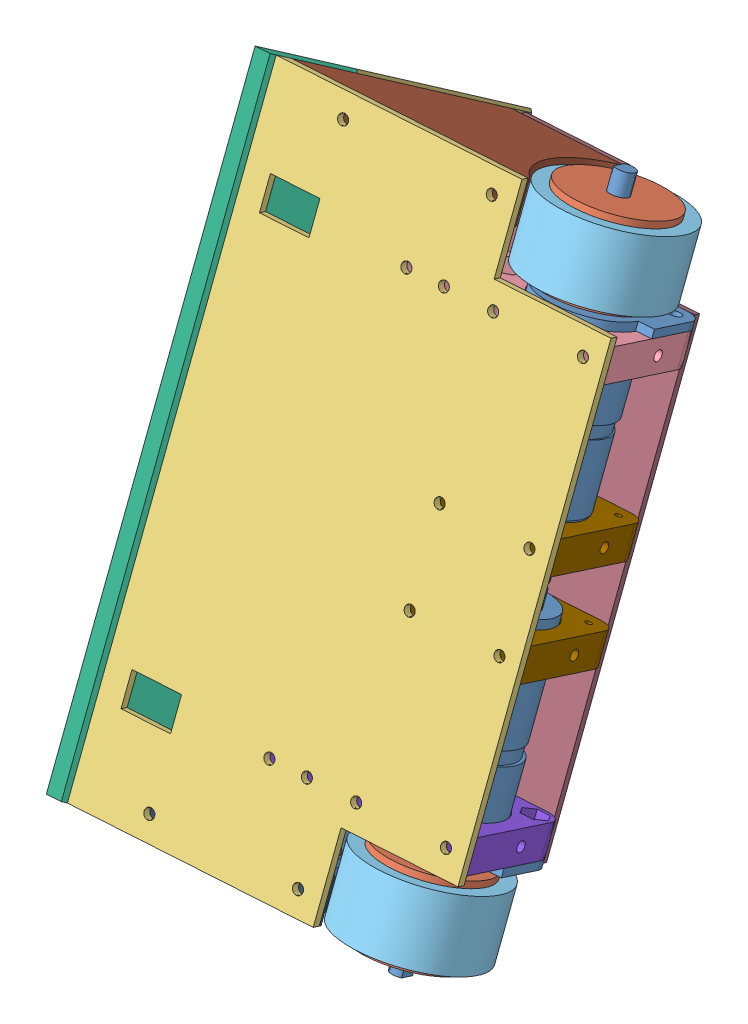
SolidWorks assembly RyO_XL, configuration Predeterminado. Lengths in mm.
Overall size (125.62 209.31 123.71).
23 component instances, 18 part files, 58 mates.
Components (placement in the parent):
- SP6_7W_EJEd6L10B-3: SP6_7W_EJEd6L10B [Predeterminado] at (18.001 16.4515 185.6838) x (-0.101969 -0.366807 -0.924692) z (0.994757 -0.030282 -0.097683) size (35 104.5 40)
- Llanta_D50L19-1: Llanta_D50L19 [Predeterminado] at (18.4238 -33.7579 205.5543) x (-0.993599 0.034235 0.107648) z (-0.112689 -0.36646 -0.923585) size (33 25 33)
- Base_chasis_RyO_XL-1: Base_chasis_RyO_XL [Predeterminado] at (-21.3225 65.5802 189.7273) x (0.00783 -0.929804 0.367972) z (0.994757 -0.030282 -0.097683) size (195 2.5 111.7)
- Soporte_motores_APYS_IZQ_XL-2: Soporte_motores_APYS_IZQ_XL [Predeterminado] at (17.2738 103.388 151.2779) x (0.994757 -0.030282 -0.097683) z (0.101969 0.366807 0.924692) size (66.72 10 35.25)
- SP6_7W_EJEd6L10B-2: SP6_7W_EJEd6L10B [Predeterminado] at (17.309 99.2039 152.9338) x (-0.101969 -0.366807 -0.924692) z (-0.994757 0.030282 0.097683) size (35 104.5 40)
- Llanta_D50L19-2: Llanta_D50L19 [Predeterminado] at (16.8862 149.4133 133.0633) x (0.676672 -0.266007 -0.686553) z (-0.736243 -0.254372 -0.627089) size (33 25 33)
- Cubierta_D42L15-1: Cubierta_D42L15 [Predeterminado] at (18.2437 -12.3724 197.0909) x (0.836326 0.207815 0.507318) z (0.548177 -0.303772 -0.779246) size (42 21 42)
- Cubierta_D42L15-2: Cubierta_D42L15 [Predeterminado] at (17.0663 128.0278 141.5267) x (0.999968 0.00783 -0.001493) z (-0.001493 0.367972 0.929836) size (42 21 42)
- Cuchilla_Garlopa-1: Cuchilla_Garlopa [Predeterminado] at (-67.5893 155.8983 153.9648) x (-0.688932 0.261701 0.675933) z (0.724784 0.2588 0.638522) size (25 195 3)
- pololu-38-khz-ir-proximity-sensor-1: pololu-38-khz-ir-proximity-sensor [Predeterminado] at (-51.0023 115.765 164.982) x (0.00783 -0.929804 0.367972) z (-0.101969 -0.366807 -0.924692) size (10.16 15.24 5.37)
- pololu-38-khz-ir-proximity-sensor-2: pololu-38-khz-ir-proximity-sensor [Predeterminado] at (-50.2049 21.0737 202.4563) x (0.00783 -0.929804 0.367972) z (-0.101969 -0.366807 -0.924692) size (10.16 15.24 5.37)
- Soporte_motores_APYS_DER_XL-1: Soporte_motores_APYS_DER_XL [Predeterminado] at (18.3494 -24.9248 202.0585) x (0.994757 -0.030282 -0.097683) z (0.101969 0.366807 0.924692) size (66.72 10 35.25)
- g2-high-power-motor-driver-md31a.step-1: g2-high-power-motor-driver-md31a.step [Predeterminado] at (15.7291 -43.1589 53.3885) x (-0.008523 0 0.999964) z (-0.999964 0 -0.008523) size (33.02 20.32 9.57) (hidden)
- Soporte_motores_INTERNO_APYS_XL-1: Soporte_motores_INTERNO_APYS_XL [Predeterminado] at (17.9587 21.4701 183.6977) x (0.994757 -0.030282 -0.097683) z (0.101969 0.366807 0.924692) size (39.99 10 35.25)
- Soporte_motores_INTERNO_APYS_XL-3: Soporte_motores_INTERNO_APYS_XL [Predeterminado] at (17.7395 47.5046 173.3944) x (0.994757 -0.030282 -0.097683) z (0.101969 0.366807 0.924692) size (39.99 10 35.25)
- 2022-RyO-XL-Lateral_DER-1: 2022-RyO-XL-Lateral_DER [Predeterminado] at (3.9551 -14.8948 216.1591) x (-0.994757 0.030282 0.097683) z (0.101969 0.366807 0.924692) size (76.35 12.75 35.25)
- 2022-RyO-XL-Lateral_IZQ-2: 2022-RyO-XL-Lateral_IZQ [Predeterminado] at (2.6279 142.707 153.7879) x (-0.994757 0.030282 0.097683) z (0.101969 0.366807 0.924692) size (76.35 12.75 35.25)
- Lipo_Tattu_1500_4S-1: Lipo_Tattu_1500_4S [Predeterminado] at (9.925 4.3149 149.7532) x (-0.994757 0.030282 0.097683) z (-0.101969 -0.366807 -0.924692) size (37 85 33) (hidden)
- Soporte Sensores-1: Soporte Sensores [Predeterminado] at (-31.7932 51.9347 155.4704) x (0.00783 -0.929804 0.367972) z (-0.724784 -0.2588 -0.638522) size (195 43 18.19)
- Tapa_Posterior-1: Tapa_Posterior [Predeterminado] at (-29.0129 51.1103 153.328) x (0.00783 -0.929804 0.367972) z (0.101969 0.366807 0.924692) size (195 62 2)
- CoverBateria-1: CoverBateria [Predeterminado] at (-7.1283 50.4441 151.1789) x (0.994757 -0.030282 -0.097683) z (-0.101969 -0.366807 -0.924692) size (60.29 144 41) (hidden)
- HC-SR04-1: HC-SR04 [Predeterminado] at (-20.1223 30.7171 162.7682) x (-0.00783 0.929804 -0.367972) z (0.994757 -0.030282 -0.097683) size (45 20.3 18.25)
- Plomo_Central-1: Plomo_Central [Predeterminado] at (-62.9124 13.8658 212.1241) x (0.994757 -0.030282 -0.097683) z (0.101969 0.366807 0.924692) size (60 112 23)
Mates (geometry in assembly coordinates):
- Concéntrica2: concentric anti-aligned: cylinder of SP6_7W_EJEd6L10B-3 through (18.4747 -39.8016 207.9461) axis (-0.00783 0.929804 -0.367972) radius 3; cylinder of Llanta_D50L19-1 through (18.2281 -10.5128 196.355) axis (0.00783 -0.929804 0.367972) radius 3
- Concéntrica5: concentric aligned: cylinder of Soporte_motores_APYS_IZQ_XL-2 through (17.1172 121.9841 143.9185) axis (0.00783 -0.929804 0.367972) radius 15.25; cylinder of SP6_7W_EJEd6L10B-2 through (17.1172 121.9841 143.9185) axis (0.00783 -0.929804 0.367972) radius 15
- Coincidente5: coincident anti-aligned: plane of SP6_7W_EJEd6L10B-2 through (33.5681 127.032 156.3236) normal (0.00783 -0.929804 0.367972); plane of Soporte_motores_APYS_IZQ_XL-2 through (46.4648 126.7319 155.2909) normal (-0.00783 0.929804 -0.367972)
- Concéntrica6: concentric aligned: cylinder of Soporte_motores_APYS_IZQ_XL-2 through (0.6663 116.9362 131.5133) axis (0.00783 -0.929804 0.367972) radius 1; cylinder of SP6_7W_EJEd6L10B-2 through (0.6467 119.2607 130.5934) axis (0.00783 -0.929804 0.367972) radius 2
- Coincidente6: coincident anti-aligned: plane of Base_chasis_RyO_XL-1 through (-21.5774 64.6631 187.4156) normal (-0.101969 -0.366807 -0.924692); plane of Soporte_motores_APYS_DER_XL-1 through (19.9044 -19.331 216.1601) normal (0.101969 0.366807 0.924692)
- Concéntrica8: concentric anti-aligned: cylinder of SP6_7W_EJEd6L10B-2 through (16.8353 155.457 130.6715) axis (0.00783 -0.929804 0.367972) radius 3; cylinder of Llanta_D50L19-2 through (17.082 126.1682 142.2626) axis (-0.00783 0.929804 -0.367972) radius 3
- Concéntrica10: concentric anti-aligned: cylinder of Llanta_D50L19-1 through (18.2281 -10.5128 196.355) axis (0.00783 -0.929804 0.367972) radius 15; cylinder of Cubierta_D42L15-1 through (18.4082 -31.8983 204.8183) axis (-0.00783 0.929804 -0.367972) radius 12.5
- Coincidente9: coincident anti-aligned: plane of Cubierta_D42L15-1 through (18.4082 -31.8983 204.8183) normal (0.00783 -0.929804 0.367972); plane of Llanta_D50L19-1 through (18.4082 -31.8983 204.8183) normal (-0.00783 0.929804 -0.367972)
- Concéntrica11: concentric anti-aligned: cylinder of Llanta_D50L19-2 through (17.082 126.1682 142.2626) axis (-0.00783 0.929804 -0.367972) radius 15; cylinder of Cubierta_D42L15-2 through (16.9019 147.5537 133.7992) axis (0.00783 -0.929804 0.367972) radius 12.5
- Coincidente10: coincident anti-aligned: plane of Llanta_D50L19-2 through (16.9019 147.5537 133.7992) normal (0.00783 -0.929804 0.367972); plane of Cubierta_D42L15-2 through (16.9019 147.5537 133.7992) normal (-0.00783 0.929804 -0.367972)
- Coincidente11: coincident anti-aligned: plane of Base_chasis_RyO_XL-1 through (-70.2264 198.6717 139.6216) normal (-0.724784 -0.2588 -0.638522); plane of Cuchilla_Garlopa-1 through (-57.2092 -28.7765 217.0331) normal (0.724784 0.2588 0.638522)
- Coincidente13: coincident aligned: plane of Base_chasis_RyO_XL-1 through (-20.814 -25.9927 223.2928) normal (0.00783 -0.929804 0.367972); plane of Cuchilla_Garlopa-1 through (-66.0625 -25.4135 225.7193) normal (0.00783 -0.929804 0.367972)
- Distancia8: distance = 5 mm anti-aligned: plane of pololu-38-khz-ir-proximity-sensor-2 through (-50.2049 21.0737 202.4563) normal (0.101969 0.366807 0.924692); plane of Base_chasis_RyO_XL-1 through (-21.5774 64.6631 187.4156) normal (-0.101969 -0.366807 -0.924692)
- Concéntrica18: concentric anti-aligned: cylinder of Soporte_motores_APYS_DER_XL-1 through (-12.7337 -8.138 177.1973) axis (0.101969 0.366807 0.924692) radius 1.625; cylinder of Base_chasis_RyO_XL-1 through (-8.1196 8.4604 219.0405) axis (-0.101969 -0.366807 -0.924692) radius 1.625
- Coincidente27: coincident anti-aligned: plane of Base_chasis_RyO_XL-1 through (-21.5774 64.6631 187.4156) normal (-0.101969 -0.366807 -0.924692); plane of Soporte_motores_APYS_IZQ_XL-2 through (18.8288 108.9818 165.3795) normal (0.101969 0.366807 0.924692)
- Paralelo4: parallel aligned: plane of Base_chasis_RyO_XL-1 through (-20.814 -25.9927 223.2928) normal (0.00783 -0.929804 0.367972); plane of Soporte_motores_APYS_DER_XL-1 through (50.2272 -2.5875 203.4709) normal (0.00783 -0.929804 0.367972)
- Concéntrica21: concentric anti-aligned: cylinder of SP6_7W_EJEd6L10B-3 through (18.1928 -6.3287 194.6991) axis (-0.00783 0.929804 -0.367972) radius 15; cylinder of Soporte_motores_APYS_DER_XL-1 through (18.1928 -6.3287 194.6991) axis (0.00783 -0.929804 0.367972) radius 15.25
- Concéntrica22: concentric aligned: circle of SP6_7W_EJEd6L10B-3; cylinder of Soporte_motores_APYS_DER_XL-1 through (1.742 -11.3766 182.294) axis (0.00783 -0.929804 0.367972) radius 1
- Concéntrica23: concentric anti-aligned: cylinder of SP6_7W_EJEd6L10B-3 through (31.6042 -14.6095 180.2834) axis (-0.00783 0.929804 -0.367972) radius 2; cylinder of Soporte_motores_APYS_DER_XL-1 through (31.5847 -12.285 179.3635) axis (0.00783 -0.929804 0.367972) radius 1
- Coincidente29: coincident anti-aligned: plane of SP6_7W_EJEd6L10B-3 through (4.801 -0.3724 210.0347) normal (-0.00783 0.929804 -0.367972); plane of Soporte_motores_APYS_DER_XL-1 through (50.2272 -2.5875 203.4709) normal (0.00783 -0.929804 0.367972)
- Distancia9: distance = 3 mm anti-aligned: plane of pololu-38-khz-ir-proximity-sensor-2 through (-50.229 11.2543 205.2554) normal (0.00783 -0.929804 0.367972); plane of Soporte_motores_APYS_DER_XL-1 through (39.3098 7.0405 200.8555) normal (-0.00783 0.929804 -0.367972)
- Concéntrica27: concentric anti-aligned: cylinder of Base_chasis_RyO_XL-1 through (-20.6012 127.8247 173.0673) axis (-0.101969 -0.366807 -0.924692) radius 1.625; cylinder of Soporte_motores_APYS_IZQ_XL-2 through (-25.2154 111.2263 131.2241) axis (0.101969 0.366807 0.924692) radius 1.625
- Concéntrica32: concentric anti-aligned: cylinder of Base_chasis_RyO_XL-1 through (6.5848 54.491 199.1595) axis (-0.101969 -0.366807 -0.924692) radius 1.625; cylinder of Soporte_motores_INTERNO_APYS_XL-1 through (4.3415 46.4213 178.8163) axis (0.101969 0.366807 0.924692) radius 1.625
- Concéntrica33: concentric anti-aligned: cylinder of Base_chasis_RyO_XL-1 through (34.0889 53.6538 196.4587) axis (-0.101969 -0.366807 -0.924692) radius 1.625; cylinder of Soporte_motores_INTERNO_APYS_XL-1 through (31.8457 45.584 176.1155) axis (0.101969 0.366807 0.924692) radius 1.625
- Coincidente40: coincident anti-aligned: plane of Base_chasis_RyO_XL-1 through (-21.5774 64.6631 187.4156) normal (-0.101969 -0.366807 -0.924692); plane of Soporte_motores_INTERNO_APYS_XL-1 through (19.5137 27.0639 197.7992) normal (0.101969 0.366807 0.924692)
- Concéntrica34: concentric anti-aligned: cylinder of Base_chasis_RyO_XL-1 through (6.3656 80.5256 188.8563) axis (-0.101969 -0.366807 -0.924692) radius 1.625; cylinder of Soporte_motores_INTERNO_APYS_XL-3 through (4.1223 72.4558 168.5131) axis (0.101969 0.366807 0.924692) radius 1.625
- Concéntrica35: concentric anti-aligned: cylinder of Base_chasis_RyO_XL-1 through (33.8697 79.6883 186.1555) axis (-0.101969 -0.366807 -0.924692) radius 1.625; cylinder of Soporte_motores_INTERNO_APYS_XL-3 through (31.6264 71.6185 165.8122) axis (0.101969 0.366807 0.924692) radius 1.625
- Coincidente41: coincident anti-aligned: plane of Base_chasis_RyO_XL-1 through (-21.5774 64.6631 187.4156) normal (-0.101969 -0.366807 -0.924692); plane of Soporte_motores_INTERNO_APYS_XL-3 through (19.2945 53.0984 187.496) normal (0.101969 0.366807 0.924692)
- Distancia12: distance = 3 mm anti-aligned: plane of pololu-38-khz-ir-proximity-sensor-1 through (-66.266 115.8538 165.5312) normal (-0.00783 0.929804 -0.367972); plane of Soporte_motores_APYS_IZQ_XL-2 through (38.3907 116.7572 157.4344) normal (0.00783 -0.929804 0.367972)
- Coincidente43: coincident aligned: plane of pololu-38-khz-ir-proximity-sensor-1 through (-51.0023 115.765 164.982) normal (0.101969 0.366807 0.924692); plane of pololu-38-khz-ir-proximity-sensor-2 through (-50.2049 21.0737 202.4563) normal (0.101969 0.366807 0.924692)
- Coincidente44: coincident aligned: plane of pololu-38-khz-ir-proximity-sensor-1 through (-51.1059 115.3923 164.0425) normal (0.994757 -0.030282 -0.097683); plane of pololu-38-khz-ir-proximity-sensor-2 through (-50.3085 20.7011 201.5168) normal (0.994757 -0.030282 -0.097683)
- Concéntrica36: concentric aligned: cylinder of 2022-RyO-XL-Lateral_DER-1 through (-5.9837 -30.8945 191.5681) axis (0.101969 0.366807 0.924692) radius 1.625; cylinder of Base_chasis_RyO_XL-1 through (-2.9632 -20.0292 218.9587) axis (0.101969 0.366807 0.924692) radius 1.625
- Coincidente45: coincident anti-aligned: plane of Base_chasis_RyO_XL-1 through (-21.5774 64.6631 187.4156) normal (-0.101969 -0.366807 -0.924692); plane of 2022-RyO-XL-Lateral_DER-1 through (4.0549 -26.7498 220.8508) normal (0.101969 0.366807 0.924692)
- Concéntrica40: concentric anti-aligned: cylinder of Base_chasis_RyO_XL-1 through (-47.4867 -14.9747 232.6779) axis (-0.101969 -0.366807 -0.924692) radius 1.625; cylinder of 2022-RyO-XL-Lateral_DER-1 through (-51.5268 -29.5082 196.0403) axis (0.101969 0.366807 0.924692) radius 1.625
- Coincidente47: coincident anti-aligned: plane of Base_chasis_RyO_XL-1 through (-21.5774 64.6631 187.4156) normal (-0.101969 -0.366807 -0.924692); plane of 2022-RyO-XL-Lateral_IZQ-2 through (2.7278 130.852 158.4795) normal (0.101969 0.366807 0.924692)
- Concéntrica41: concentric aligned: cylinder of Base_chasis_RyO_XL-1 through (-4.3804 148.2653 152.3558) axis (0.101969 0.366807 0.924692) radius 1.625; cylinder of 2022-RyO-XL-Lateral_IZQ-2 through (-7.4008 137.4 124.9651) axis (0.101969 0.366807 0.924692) radius 1.625
- Concéntrica42: concentric anti-aligned: cylinder of Base_chasis_RyO_XL-1 through (-48.9038 153.3198 166.075) axis (-0.101969 -0.366807 -0.924692) radius 1.625; cylinder of 2022-RyO-XL-Lateral_IZQ-2 through (-52.944 138.7863 129.4374) axis (0.101969 0.366807 0.924692) radius 1.625
- Distancia14: distance = 55 mm aligned: plane of Lipo_Tattu_1500_4S-1 through (9.925 4.3149 149.7532) normal (0.00783 -0.929804 0.367972); plane of Base_chasis_RyO_XL-1 through (-20.814 -25.9927 223.2928) normal (0.00783 -0.929804 0.367972)
- Distancia16: distance = 2 mm anti-aligned: plane of Llanta_D50L19-2 through (17.082 126.1682 142.2626) normal (0.00783 -0.929804 0.367972); plane of SP6_7W_EJEd6L10B-2 through (33.5485 129.3565 155.4037) normal (-0.00783 0.929804 -0.367972)
- Distancia17: distance = 2 mm anti-aligned: plane of Llanta_D50L19-1 through (18.2281 -10.5128 196.355) normal (-0.00783 0.929804 -0.367972); plane of SP6_7W_EJEd6L10B-3 through (4.8206 -2.6969 210.9546) normal (0.00783 -0.929804 0.367972)
- Concéntrica43: concentric anti-aligned: cylinder of 2022-RyO-XL-Lateral_IZQ-2 through (-35.5929 143.1766 138.4632) axis (-0.724784 -0.2588 -0.638522) radius 1.625; cylinder of Soporte Sensores-1 through (-45.015 139.8122 130.1624) axis (0.724784 0.2588 0.638522) radius 1.625
- Concéntrica47: concentric anti-aligned: cylinder of 2022-RyO-XL-Lateral_DER-1 through (-34.1659 -26.2801 205.5261) axis (-0.724784 -0.2588 -0.638522) radius 1.625; cylinder of Soporte Sensores-1 through (-43.5881 -29.6445 197.2253) axis (0.724784 0.2588 0.638522) radius 1.625
- Coincidente48: coincident anti-aligned: plane of 2022-RyO-XL-Lateral_IZQ-2 through (-69.6738 133.056 165.5892) normal (-0.724784 -0.2588 -0.638522); plane of Soporte Sensores-1 through (-31.7932 51.9347 155.4704) normal (0.724784 0.2588 0.638522)
- Coincidente49: coincident anti-aligned: plane of Cuchilla_Garlopa-1 through (-59.3836 -29.5529 215.1176) normal (0.688932 -0.261701 -0.675933); plane of Soporte Sensores-1 through (-59.3836 -29.5529 215.1176) normal (-0.688932 0.261701 0.675933)
- Concéntrica48: concentric aligned: cylinder of 2022-RyO-XL-Lateral_IZQ-2 through (-18.9647 149.2906 153.5584) axis (-0.101969 -0.366807 -0.924692) radius 1.625; cylinder of Tapa_Posterior-1 through (-22.5591 136.3603 120.9621) axis (-0.101969 -0.366807 -0.924692) radius 1.625
- Concéntrica49: concentric aligned: cylinder of 2022-RyO-XL-Lateral_DER-1 through (-17.5377 -20.1661 220.6213) axis (-0.101969 -0.366807 -0.924692) radius 1.625; cylinder of Tapa_Posterior-1 through (-21.1322 -33.0965 188.025) axis (-0.101969 -0.366807 -0.924692) radius 1.625
- Coincidente50: coincident anti-aligned: plane of 2022-RyO-XL-Lateral_IZQ-2 through (-32.3805 121.67 127.8725) normal (-0.101969 -0.366807 -0.924692); plane of Tapa_Posterior-1 through (-28.809 51.8439 155.1773) normal (0.101969 0.366807 0.924692)
- Coincidente51: coincident anti-aligned: plane of Lipo_Tattu_1500_4S-1 through (29.345 88.8403 131.9259) normal (0.101969 0.366807 0.924692); plane of Tapa_Posterior-1 through (-29.0129 51.1103 153.328) normal (-0.101969 -0.366807 -0.924692)
- Distancia18: distance = 3 mm aligned: plane of Lipo_Tattu_1500_4S-1 through (25.98 76.7357 101.411) normal (0.994757 -0.030282 -0.097683); plane of Tapa_Posterior-1 through (33.4258 -16.5145 175.431) normal (0.994757 -0.030282 -0.097683)
- Concéntrica50: concentric anti-aligned: cylinder of Tapa_Posterior-1 through (18.4383 109.8978 126.9384) axis (-0.101969 -0.366807 -0.924692) radius 1.625; cylinder of CoverBateria-1 through (17.9284 108.0638 122.3149) axis (0.101969 0.366807 0.924692) radius 1.625
- Concéntrica51: concentric anti-aligned: cylinder of Tapa_Posterior-1 through (19.4405 -9.1171 174.0388) axis (-0.101969 -0.366807 -0.924692) radius 1.625; cylinder of CoverBateria-1 through (18.9306 -10.9511 169.4153) axis (0.101969 0.366807 0.924692) radius 1.625
- Coincidente53: coincident anti-aligned: plane of Tapa_Posterior-1 through (-29.0129 51.1103 153.328) normal (-0.101969 -0.366807 -0.924692); plane of CoverBateria-1 through (-7.1283 50.4441 151.1789) normal (0.101969 0.366807 0.924692)
- Concéntrica52: concentric: cylinder of Soporte Sensores-1 through (-61.4688 68.725 163.4165) axis (0.994757 -0.030282 -0.097683) radius 8.25; cylinder of HC-SR04-1 through (-19.3469 67.4427 159.2803) axis (-0.994757 0.030282 0.097683) radius 7.975
- Concéntrica53: concentric: cylinder of Soporte Sensores-1 through (-61.2664 44.6895 172.9286) axis (0.994757 -0.030282 -0.097683) radius 8.25; cylinder of HC-SR04-1 through (-19.1445 43.4073 168.7923) axis (-0.994757 0.030282 0.097683) radius 7.975
- Coincidente54: coincident: circle of Soporte Sensores-1; plane of HC-SR04-1 through (-31.3834 67.8091 160.4622) normal (-0.994757 0.030282 0.097683)
- Coincidente55: coincident anti-aligned: plane of Base_chasis_RyO_XL-1 through (-21.5774 64.6631 187.4156) normal (-0.101969 -0.366807 -0.924692); plane of Plomo_Central-1 through (-4.1039 116.1869 165.0502) normal (0.101969 0.366807 0.924692)
- Distancia19: distance = 3 mm anti-aligned: plane of Plomo_Central-1 through (-6.4492 107.7503 143.7823) normal (0.994757 -0.030282 -0.097683); plane of Soporte_motores_INTERNO_APYS_XL-3 through (-4.4235 68.668 145.8145) normal (-0.994757 0.030282 0.097683)
- Distancia20: distance = 3 mm anti-aligned: plane of Plomo_Central-1 through (-63.7893 118.0038 170.9112) normal (-0.00783 0.929804 -0.367972); plane of Soporte_motores_APYS_IZQ_XL-2 through (38.3907 116.7572 157.4344) normal (0.00783 -0.929804 0.367972)
